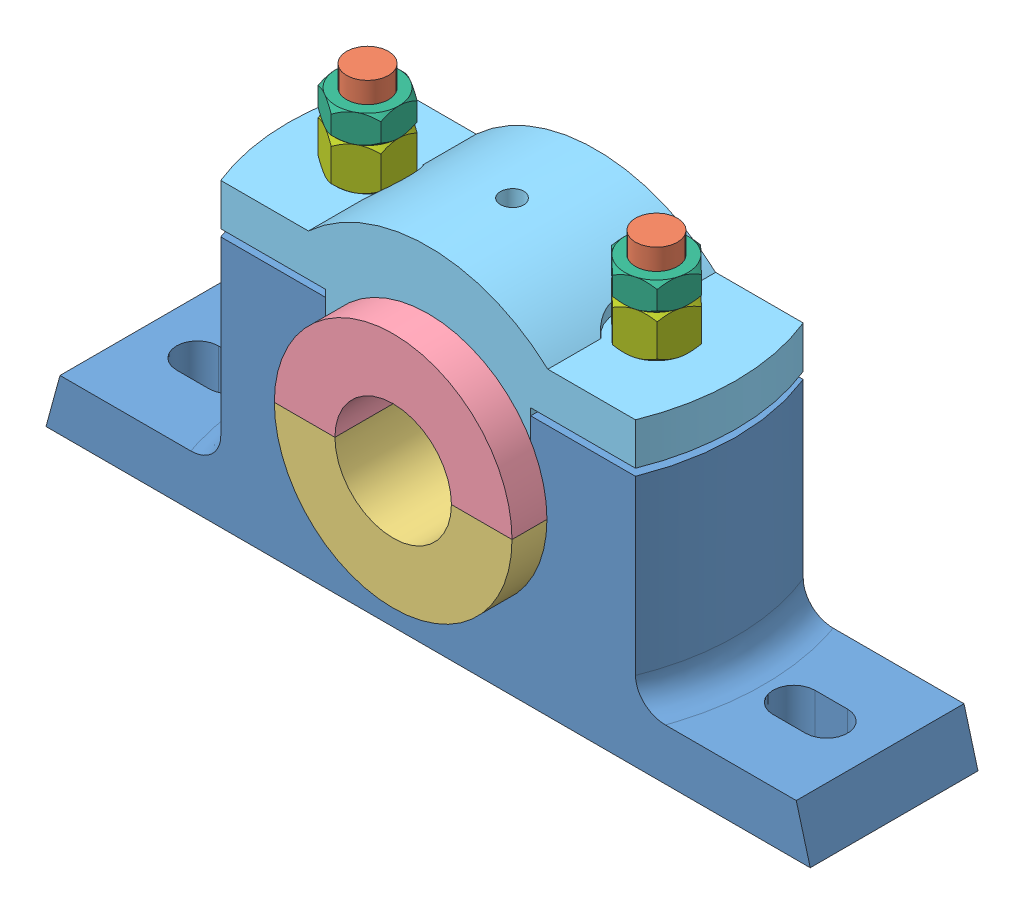
SolidWorks assembly Assem1, configuration Default. Lengths in mm.
Overall size (164 85 51).
10 component instances, 7 part files, 23 mates.
Components (placement in the parent):
- casting-2: casting [Default] at (35.1887 -186.9952 -58.0234) size (164 54 36)
- bolt-2: bolt [Default] at (66.1887 -178.9952 -58.0234) x (0.293102 0 -0.956081) z (0 -1 0) size (19 19 85)
- bolt-3: bolt [Default] at (4.1887 -178.9952 -58.0234) x (1 0 0) z (0 -1 0) size (19 19 85)
- brass 2-3: brass 2 [Default] at (35.1887 -150.4952 -58.0234) x (0 0 1) z (0 -1 0) size (51 51 25.5)
- brass 1-3: brass 1 [Default] at (35.1887 -150.4952 -58.0234) x (0 0 -1) z (0 1 0) size (51 51 25.5)
- cap-2: cap [Default] at (35.1887 -150.4952 -58.0234) size (96 32 36)
- lock nut-2: lock nut [Default] at (66.1887 -110.4952 -58.0234) x (-0.69658 0 0.717479) z (0 1 0) size (13.5 15.59 6)
- nut 1-2: nut 1 [Default] at (66.1887 -117.9952 -58.0234) x (0.273065 0 0.961995) z (0 1 0) size (13.5 15.59 9)
- lock nut-3: lock nut [Default] at (4.1887 -110.4952 -58.0234) x (1 0 0) z (0 1 0) size (13.5 15.59 6)
- nut 1-3: nut 1 [Default] at (4.1887 -117.9952 -58.0234) x (1 0 0) z (0 1 0) size (13.5 15.59 9)
Mates (geometry in assembly coordinates):
- Coincident3: coincident anti-aligned: plane of casting-2 through (35.1887 -178.9952 -58.0234) normal (0 -1 0); plane of bolt-2 through (66.1887 -178.9952 -58.0234) normal (0 1 0)
- Coincident4: coincident anti-aligned: circle of casting-2; cylinder of bolt-2 through (66.1887 -102.9952 -58.0234) axis (0 -1 0) radius 4.5
- Coincident5: coincident anti-aligned: plane of casting-2 through (35.1887 -178.9952 -58.0234) normal (0 -1 0); plane of bolt-3 through (4.1887 -178.9952 -58.0234) normal (0 1 0)
- Concentric2: concentric anti-aligned: cylinder of casting-2 through (4.1887 -186.9952 -58.0234) axis (0 1 0) radius 4.5; cylinder of bolt-3 through (4.1887 -102.9952 -58.0234) axis (0 -1 0) radius 4.5
- Coincident7: coincident aligned: plane of casting-2 through (35.1887 -173.9952 -58.0234) normal (0 1 0); circle of brass 2-3
- Parallel1: parallel aligned: cylinder of casting-2 through (35.1887 -148.9952 -40.0234) axis (0 0 -1) radius 19; cylinder of brass 2-3 through (35.1887 -150.4952 -97.9426) axis (0 0 -1) radius 17.5
- Concentric6: concentric aligned: cylinder of casting-2 through (35.1887 -173.9952 -58.0234) axis (0 1 0) radius 3; cylinder of brass 2-3 through (35.1887 -150.4952 -58.0234) axis (0 1 0) radius 3
- Concentric7: concentric anti-aligned: cylinder of brass 2-3 through (35.1887 -150.4952 -97.9426) axis (0 0 -1) radius 12.5; cylinder of brass 1-3 through (35.1887 -150.4952 -18.1042) axis (0 0 1) radius 12.5
- Coincident13: coincident aligned: plane of brass 2-3 through (47.6887 -150.4952 -83.5234) normal (0 0 -1); plane of brass 1-3 through (47.6887 -150.4952 -83.5234) normal (0 0 -1)
- Coincident14: coincident anti-aligned: plane of brass 2-3 through (35.1887 -150.4952 -58.0234) normal (0 1 0); plane of brass 1-3 through (35.1887 -150.4952 -58.0234) normal (0 -1 0)
- Concentric8: concentric anti-aligned: cylinder of bolt-3 through (4.1887 -102.9952 -58.0234) axis (0 -1 0) radius 4.5; circle of cap-2
- Concentric9: concentric aligned: cylinder of bolt-2 through (66.1887 -102.9952 -58.0234) axis (0 -1 0) radius 4.5; cylinder of cap-2 through (66.1887 -112.4952 -58.0234) axis (0 -1 0) radius 4.2217
- Concentric10: concentric anti-aligned: cylinder of brass 1-3 through (35.1887 -150.4952 -18.1042) axis (0 0 1) radius 19; cylinder of cap-2 through (35.1887 -150.4952 -40.0234) axis (0 0 -1) radius 19
- Concentric12: concentric anti-aligned: cylinder of bolt-2 through (66.1887 -102.9952 -58.0234) axis (0 -1 0) radius 4.5; cylinder of nut 1-2 through (66.1887 -113.4952 -58.0234) axis (0 1 0) radius 4.5
- Concentric13: concentric anti-aligned: cylinder of bolt-2 through (66.1887 -102.9952 -58.0234) axis (0 -1 0) radius 4.5; cylinder of lock nut-2 through (66.1887 -107.4952 -58.0234) axis (0 1 0) radius 4.5
- Coincident20: coincident anti-aligned: plane of cap-2 through (84.1887 -122.4952 -40.0234) normal (0 1 0); plane of nut 1-2 through (66.1887 -122.4952 -58.0234) normal (0 -1 0)
- Coincident21: coincident anti-aligned: plane of lock nut-2 through (66.1887 -113.4952 -58.0234) normal (0 -1 0); plane of nut 1-2 through (66.1887 -113.4952 -58.0234) normal (0 1 0)
- Coincident22: coincident aligned: plane of lock nut-2 through (71.7809 -107.4952 -52.5941) normal (0.969645 0 0.244516); plane of nut 1-2 through (71.7809 -113.4952 -52.5941) normal (0.969645 0 0.244516)
- Coincident23: coincident anti-aligned: plane of cap-2 through (9.4982 -122.4952 -40.0234) normal (0 1 0); plane of nut 1-3 through (4.1887 -122.4952 -58.0234) normal (0 -1 0)
- Concentric14: concentric anti-aligned: cylinder of bolt-3 through (4.1887 -102.9952 -58.0234) axis (0 -1 0) radius 4.5; cylinder of nut 1-3 through (4.1887 -113.4952 -58.0234) axis (0 1 0) radius 4.5
- Coincident24: coincident anti-aligned: plane of lock nut-3 through (4.1887 -113.4952 -58.0234) normal (0 -1 0); plane of nut 1-3 through (4.1887 -113.4952 -58.0234) normal (0 1 0)
- Concentric16: concentric anti-aligned: cylinder of bolt-3 through (4.1887 -102.9952 -58.0234) axis (0 -1 0) radius 4.5; cylinder of lock nut-3 through (4.1887 -107.4952 -58.0234) axis (0 1 0) radius 4.5
- Coincident25: coincident aligned: plane of lock nut-3 through (-2.5613 -107.4952 -61.9205) normal (-1 0 0); plane of nut 1-3 through (-2.5613 -113.4952 -61.9205) normal (-1 0 0)
